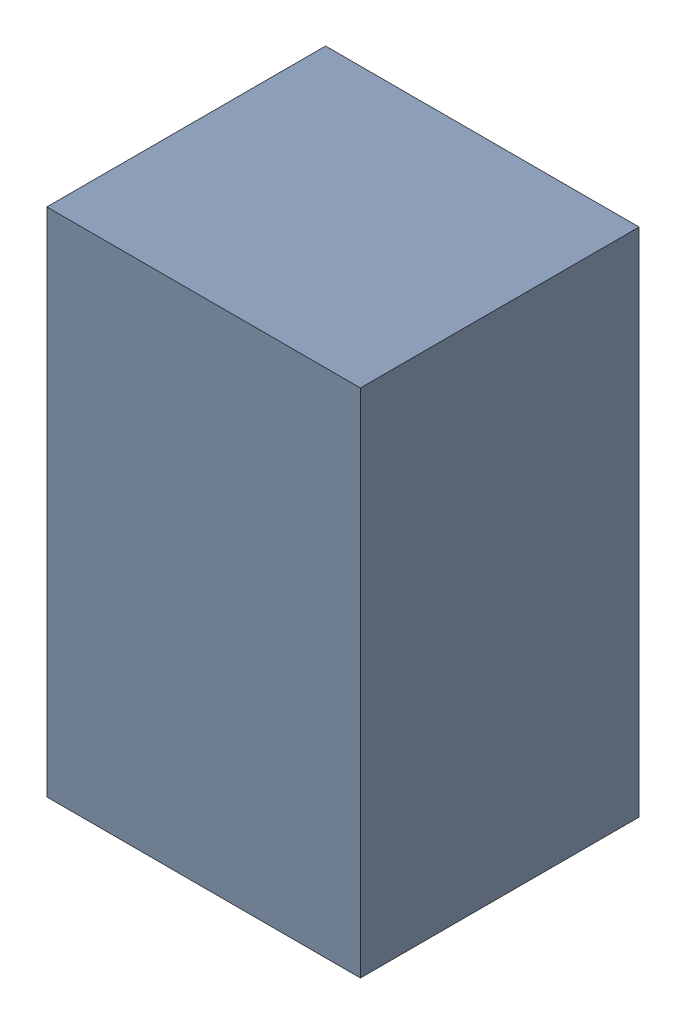
SolidWorks assembly C9_1, configuration Default. Lengths in mm.
Overall size (1.35 2.2 1.2).
2 component instances, 1 part files, 0 mates.
Components (placement in the parent):
- 407985568_1-1: 407985568_1 [Default] at (14.351 12.573 0.0127) size (1.35 2.2 1.2)
  - Extruded_8-1: Extruded_8 [Default] at origin size (1.35 2.2 1.2)
